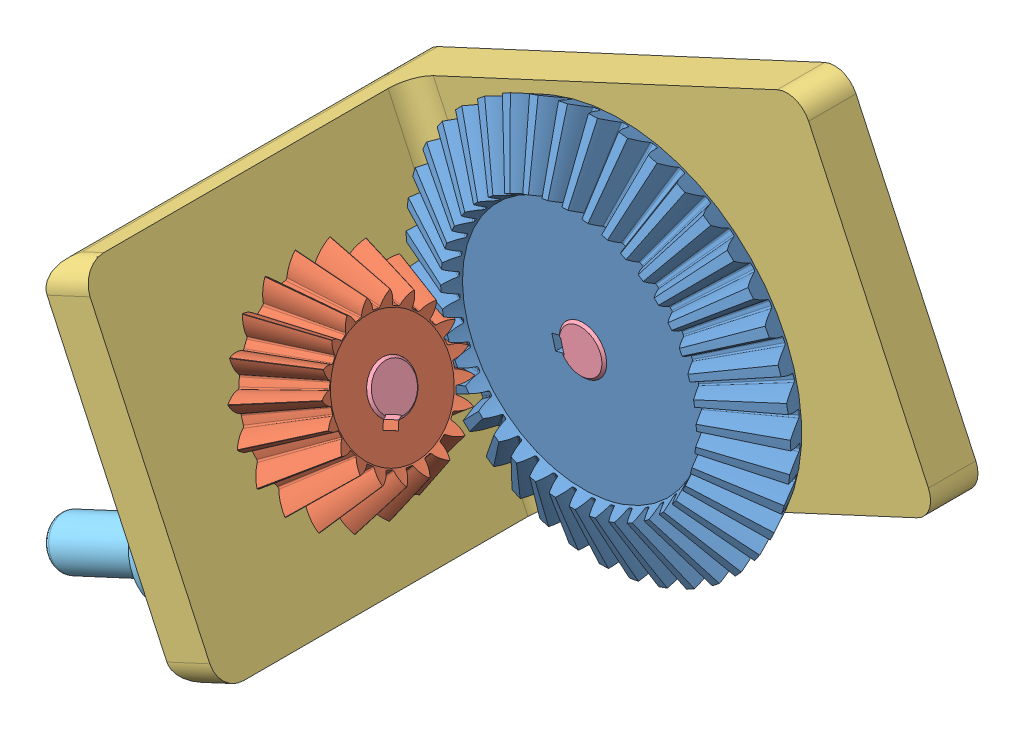
SolidWorks assembly Assem1, configuration Varsayılan. Lengths in mm.
Overall size (305.94 251.76 249.14).
7 component instances, 5 part files, 19 mates.
Components (placement in the parent):
- straight bevel gear_am-2: straight bevel gear_am [Metric - Straight bevel gear 4M 40GT 20PT 20PA 30FW ---40O40H70MD20S1] x (0 0 1) z (0.261066 -0.965321 0) size (46.14 162.34 162.34)
- straight bevel pinion_am-1: straight bevel pinion_am [Metric - Straight bevel pinion 4M20PT 40GT 20PA 30FW ---20O40H90MD20S1] at (-74.2642 -34.4975 46.8569) x (0.906927 0.421289 0) z (0.182444 -0.392756 -0.901364) size (39.95 88.85 88.85)
- TABAN-2: TABAN [Default] at (111.1136 -25.5689 -43.1431) x (-0.906927 -0.421289 0) z (0 0 -1) size (200 140 160)
- ŞAFT-1: ŞAFT [Default] at (-139.141 -64.6342 46.8569) x (-0.182444 0.392756 0.901364) z (0.906927 0.421289 0) size (20 20 100)
- ŞAFT-2: ŞAFT [Default] at (0 0 -83.2837) x (-0.261066 0.965321 0) z (0 0 1) size (20 20 100)
- Çevirme Kolu-1: Çevirme Kolu [Default] at (-129.1648 -60.0001 46.8569) x (0.379735 -0.817471 0.433062) z (-0.906927 -0.421289 0) size (90 40 60)
- Çevirme Kolu-2: Çevirme Kolu [Default] at (0 0 -72.2837) x (-0.965321 -0.261066 0) z (0 0 -1) size (90 40 60)
Mates (geometry in assembly coordinates):
- Çakışık1: coincident anti-aligned: plane of straight bevel gear_am-2 through (0 0 0) normal (0 0 -1); plane of assembly through (0 0 0) normal (0 0 1)
- Eş Merkezli1: concentric: cylinder of ? through (0 0 70.0001) axis (0 0 -1) radius 10
- Çakışık6: coincident: point of straight bevel gear_am-2; point of straight bevel pinion_am-1
- Dik Açı1: perpendicular: line of straight bevel gear_am-2 through (0 0 -10) axis (0 0 1); line of straight bevel pinion_am-1 through (-83.3335 -38.7104 46.8569) axis (0.906927 0.421289 0)
- GearMate1: gear = 40 : 20 mm: circle of straight bevel pinion_am-1; circle of straight bevel gear_am-2
- Eş Merkezli2: concentric anti-aligned: cylinder of straight bevel pinion_am-1 through (7.3592 3.4185 46.8569) axis (-0.906927 -0.421289 0) radius 10; cylinder of TABAN-2 through (-99.7619 -46.3418 46.8569) axis (0.906927 0.421289 0) radius 10
- Eş Merkezli3: concentric anti-aligned: cylinder of straight bevel gear_am-2 through (0 0 70.0001) axis (0 0 -1) radius 10; cylinder of TABAN-2 through (0 0 -43.1431) axis (0 0 1) radius 10
- Eş Merkezli4: concentric anti-aligned: cylinder of TABAN-2 through (-99.7619 -46.3418 46.8569) axis (0.906927 0.421289 0) radius 10; cylinder of ŞAFT-1 through (-48.4483 -22.5054 46.8569) axis (-0.906927 -0.421289 0) radius 10
- Eş Merkezli5: concentric anti-aligned: cylinder of TABAN-2 through (0 0 -43.1431) axis (0 0 1) radius 10; cylinder of ŞAFT-2 through (0 0 16.7163) axis (0 0 -1) radius 10
- Paralel4: parallel anti-aligned: plane of straight bevel pinion_am-1 through (4.7108 9.1201 35.3106) normal (0.111708 -0.240479 0.964205); plane of ŞAFT-1 through (-77.7684 -30.5968 39.9387) normal (-0.111708 0.240479 -0.964205)
- Çakışık12: coincident anti-aligned: circle of straight bevel gear_am-2; circle of ŞAFT-2
- Paralel11: parallel anti-aligned: plane of straight bevel gear_am-2 through (-10.4725 7.9477 70.0001) normal (0.637614 -0.770356 0); plane of ŞAFT-2 through (-7.412 4.25 -13.2837) normal (-0.637614 0.770356 0)
- Eş Merkezli6: concentric anti-aligned: cylinder of ŞAFT-1 through (-48.4483 -22.5054 46.8569) axis (-0.906927 -0.421289 0) radius 10; cylinder of Çevirme Kolu-1 through (-138.234 -64.213 46.8569) axis (0.906927 0.421289 0) radius 10
- Paralel15: parallel anti-aligned: plane of ŞAFT-1 through (-120.6775 -56.908 38.3478) normal (-0.111708 0.240479 -0.964205); plane of Çevirme Kolu-1 through (-138.3559 -63.9506 34.491) normal (0.111708 -0.240479 0.964205)
- Çakışık23: coincident anti-aligned: plane of straight bevel pinion_am-1 through (-49.3552 -22.9267 46.8569) normal (0.906927 0.421289 0); circle of ŞAFT-1
- Eş Merkezli7: concentric anti-aligned: cylinder of ŞAFT-2 through (0 0 16.7163) axis (0 0 -1) radius 10; cylinder of Çevirme Kolu-2 through (0 0 -82.2837) axis (0 0 1) radius 10
- Paralel16: parallel anti-aligned: plane of ŞAFT-2 through (-2.7898 8.0757 -63.2837) normal (-0.637614 0.770356 0); plane of Çevirme Kolu-2 through (-5.3403 11.1571 -82.2837) normal (0.637614 -0.770356 0)
- Çakışık25: coincident anti-aligned: circle of ŞAFT-1; circle of Çevirme Kolu-1
- Çakışık26: coincident anti-aligned: circle of ŞAFT-2; circle of Çevirme Kolu-2
